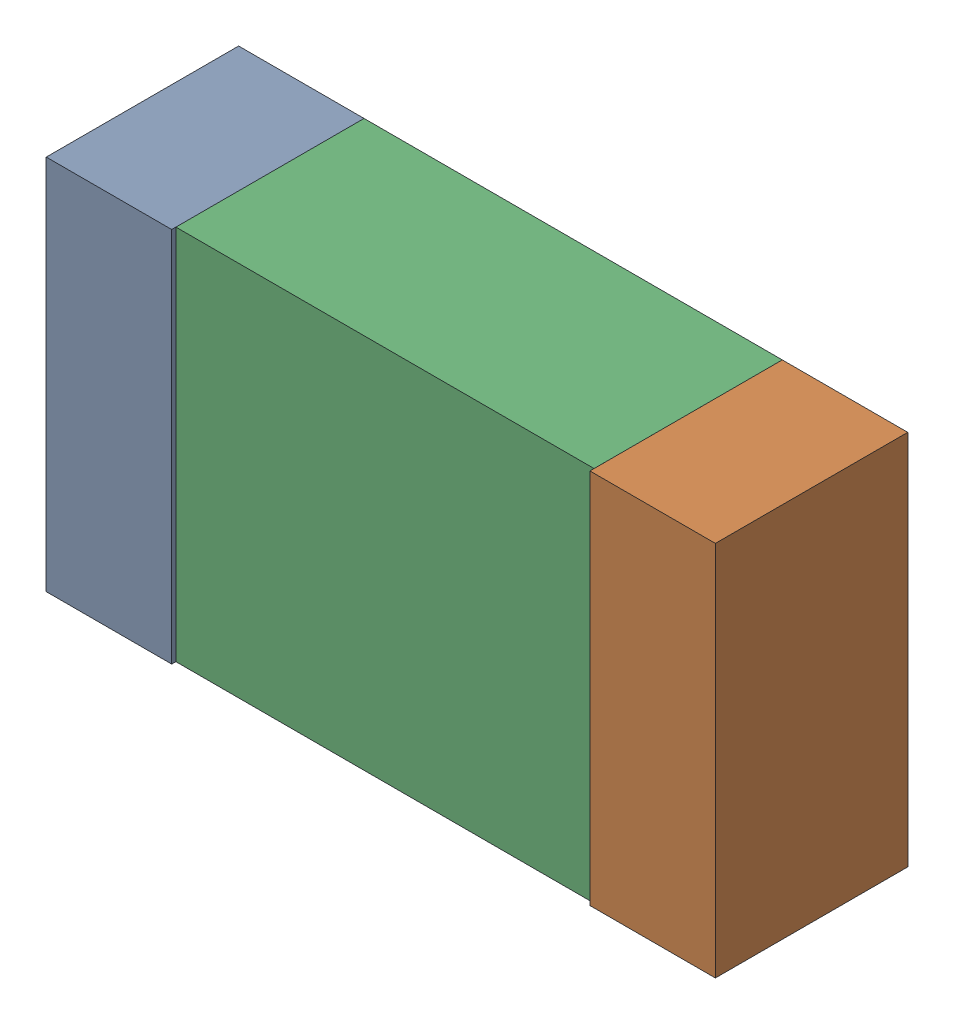
SolidWorks assembly C6, configuration Default. Lengths in mm.
Overall size (1.6 0.9 0.46).
6 component instances, 2 part files, 0 mates.
Components (placement in the parent):
- 870942080-1: 870942080 [Default] at (72.7044 4.138 0) size (0.3 0.9 0.46)
  - Extruded_15-1: Extruded_15 [Default] at origin size (0.3 0.9 0.46)
- 870942080-2: 870942080 [Default] at (74.0044 4.138 0) size (0.3 0.9 0.46)
  - Extruded_15-1: Extruded_15 [Default] at origin size (0.3 0.9 0.46)
- 870942240-1: 870942240 [Default] at (73.3544 4.138 0) size (1 0.9 0.45)
  - Extruded_14-1: Extruded_14 [Default] at origin size (1 0.9 0.45)
